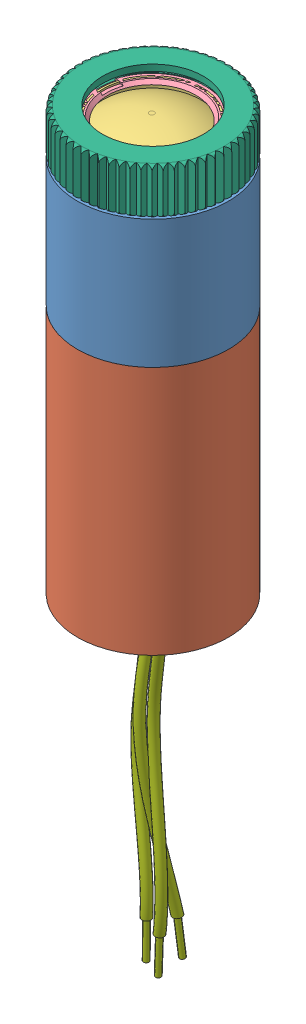
SolidWorks assembly Laser Diode Module, configuration Default. Lengths in mm.
Overall size (12.77 59.55 13.15).
7 component instances, 7 part files, 11 mates.
Components (placement in the parent):
- LD module diode mount back nut-1: LD module diode mount back nut [Default] at (-29.8165 5.6939 10.1669) size (12 16.05 12.21)
- LD module body-1: LD module body [Default] at (-29.8165 -14.5006 10.1669) x (0.999982 0 -0.006001) z (0.006001 0 0.999982) size (12 20.05 13.08)
- G-2 colimating lens-1: G-2 colimating lens [Default] at (-29.9063 12.9338 10.1669) size (8.06 5.78 8.06)
- G-2 lens focusable mount-1: G-2 lens focusable mount [Default] at (-29.9063 10.9338 10.1669) x (0.993643 0 0.112577) z (-0.112577 0 0.993643) size (9.01 8.01 10.39)
- LD module tension spring-2: LD module tension spring [Default] at (-29.8165 10.9338 10.1669) size (8.46 6.4 9.76)
- Lens Focusing Ring-1: Lens Focusing Ring [Default] at (-29.8165 15.7939 10.1669) x (-0.998124 0 -0.061226) z (0 1 0) size (12.06 12.06 3.9)
- Mitsubishi ML501P73 500mW 638nm Laser Diode with leads-1: Mitsubishi ML501P73 500mW 638nm Laser Diode with leads [Default] at (-29.8165 0.2494 10.1669) x (0.917172 0 0.398492) z (-0.398492 0 0.917172) size (5.58 43.98 5.49)
Mates (geometry in assembly coordinates):
- Lock1: lock: unknown of LD module diode mount back nut-1; unknown of LD module body-1
- Lock4: lock: unknown of G-2 colimating lens-1; unknown of G-2 lens focusable mount-1
- Lock2: lock: unknown of G-2 colimating lens-1; unknown of G-2 lens focusable mount-1
- Lock3: lock: unknown of LD module diode mount back nut-1; unknown of LD module body-1
- Lock5: lock: unknown of LD module diode mount back nut-1; unknown of LD module body-1
- Lock6: lock: unknown of LD module diode mount back nut-1; unknown of LD module tension spring-2
- Lock7: lock: unknown of G-2 lens focusable mount-1; unknown of LD module tension spring-2
- Lock9: lock: unknown of LD module diode mount back nut-1; unknown of Lens Focusing Ring-1
- Lock8: lock: unknown of LD module diode mount back nut-1; unknown of Lens Focusing Ring-1
- Concentric2: concentric aligned: cylinder of LD module diode mount back nut-1 through (-29.8165 1.4494 10.1669) axis (0 -1 0) radius 2.8; cylinder of Mitsubishi ML501P73 500mW 638nm Laser Diode with leads-1 through (-29.8165 1.4494 10.1669) axis (0 -1 0) radius 2.8
- Coincident2: coincident anti-aligned: plane of LD module diode mount back nut-1 through (-29.8165 1.4494 10.1669) normal (0 -1 0); plane of Mitsubishi ML501P73 500mW 638nm Laser Diode with leads-1 through (-29.8165 1.4494 10.1669) normal (0 1 0)
